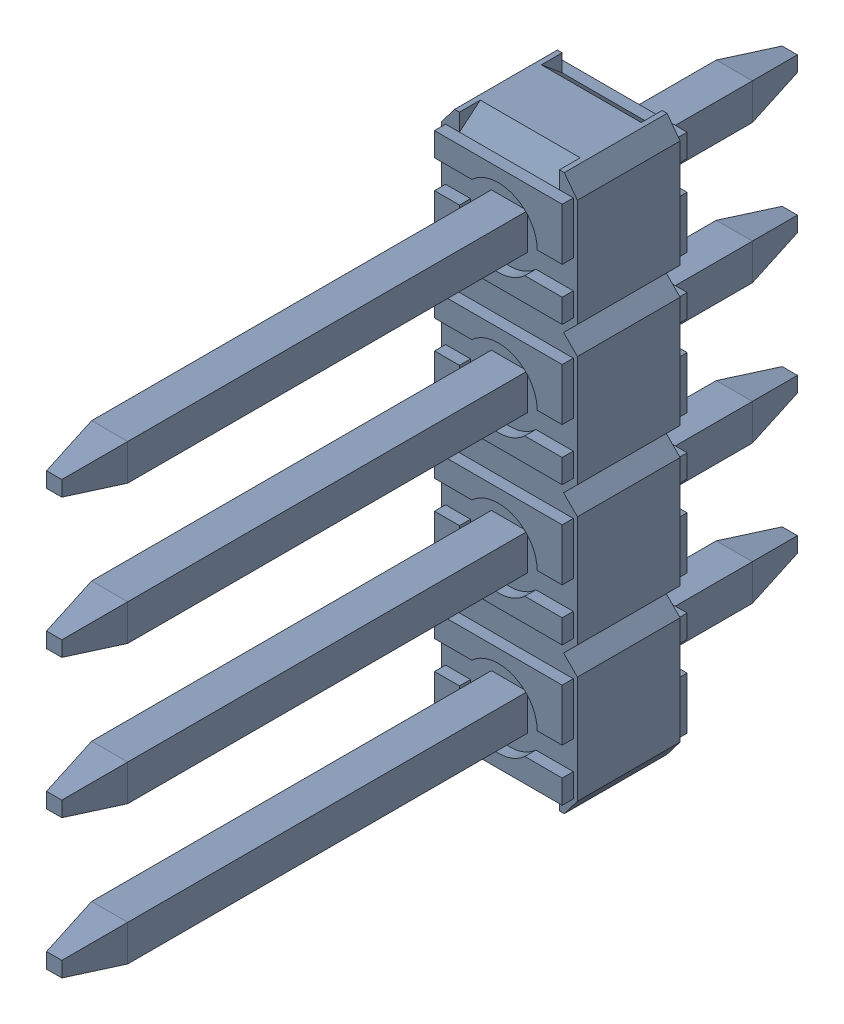
SolidWorks assembly STM, configuration Default. Lengths in mm.
Overall size (2.49 10.16 13.46).
2 component instances, 1 part files, 0 mates.
Components (placement in the parent):
- 022284041-1: 022284041 [Default] at (458.4998 271.6898 1.1706) x (0 1 0) z (1 0 0) size (10.16 13.46 2.49)
  - Open CASCADE STEP translator 6.8 1.9.1.1-1: Open CASCADE STEP translator 6.8 1.9.1.1 [Default] at origin size (10.16 13.46 2.49)
